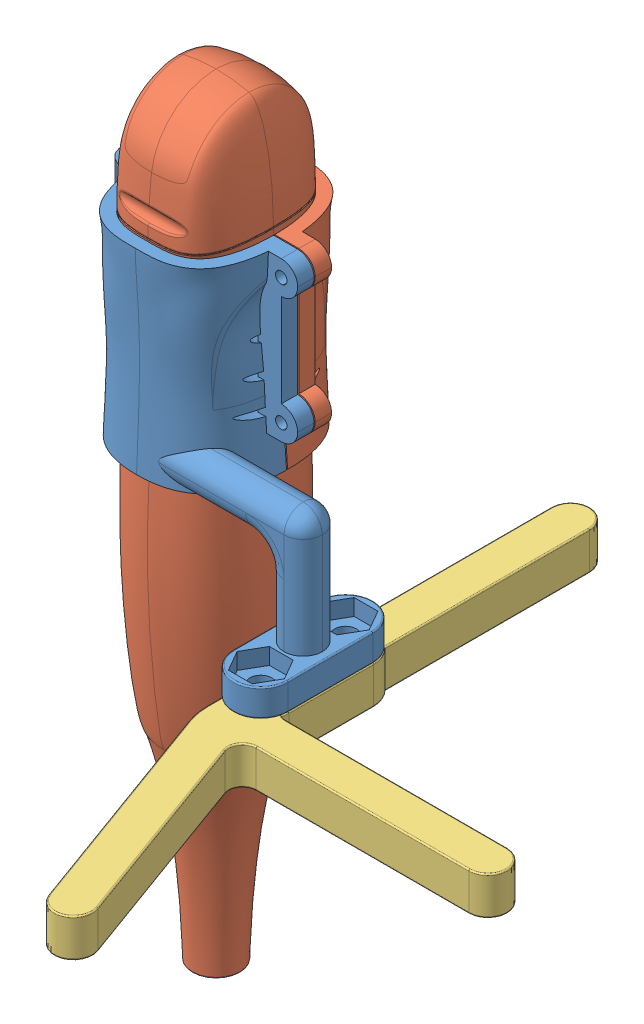
SolidWorks assembly TelemedMC10_ProbeHolder_Assembly, configuration Default. Lengths in mm.
Overall size (93.73 141.01 113.09).
3 component instances, 3 part files, 4 mates.
Components (placement in the parent):
- TelemedMC10_ProbeHolder_MarkedSide-1: TelemedMC10_ProbeHolder_MarkedSide [Default] at (7.6724 150.7644 98.3826) size (48.83 141.01 35.97)
- TelemedMC10_ProbeHolder_UnmarkedSide-1: TelemedMC10_ProbeHolder_UnmarkedSide [Default] at (7.6724 150.7644 118.3826) size (35.33 141.01 28.91)
- TelemedMC10_ProbeHolder_OpticalTracker-1: TelemedMC10_ProbeHolder_OpticalTracker [Default] at (37.6849 66.7612 138.0926) x (0 1 0) z (0 0 -1) size (7.03 54.9 113.09)
Mates (geometry in assembly coordinates):
- Concentric1: concentric aligned: cylinder of TelemedMC10_ProbeHolder_MarkedSide-1 through (-6.6453 83.6874 118.3826) axis (0 1 0) radius 1.15; cylinder of TelemedMC10_ProbeHolder_UnmarkedSide-1 through (-6.6453 105.7644 118.3826) axis (0 1 0) radius 1.15
- Distance1: distance = 0.2 mm anti-aligned: plane of TelemedMC10_ProbeHolder_UnmarkedSide-1 through (-6.6453 117.7644 118.3826) normal (0 1 0); plane of TelemedMC10_ProbeHolder_MarkedSide-1 through (-6.6453 117.9644 118.3826) normal (0 -1 0)
- Parallel1: parallel anti-aligned: plane of TelemedMC10_ProbeHolder_MarkedSide-1 through (-3.6453 159.0948 118.4826) normal (0 0 -1); plane of TelemedMC10_ProbeHolder_UnmarkedSide-1 through (-3.6453 159.0948 118.2826) normal (0 0 1)
- Coincident3: coincident anti-aligned: plane of TelemedMC10_ProbeHolder_MarkedSide-1 through (7.6724 73.7612 118.3826) normal (0 -1 0); plane of TelemedMC10_ProbeHolder_OpticalTracker-1 through (34.1849 73.7612 80.0926) normal (0 1 0)
